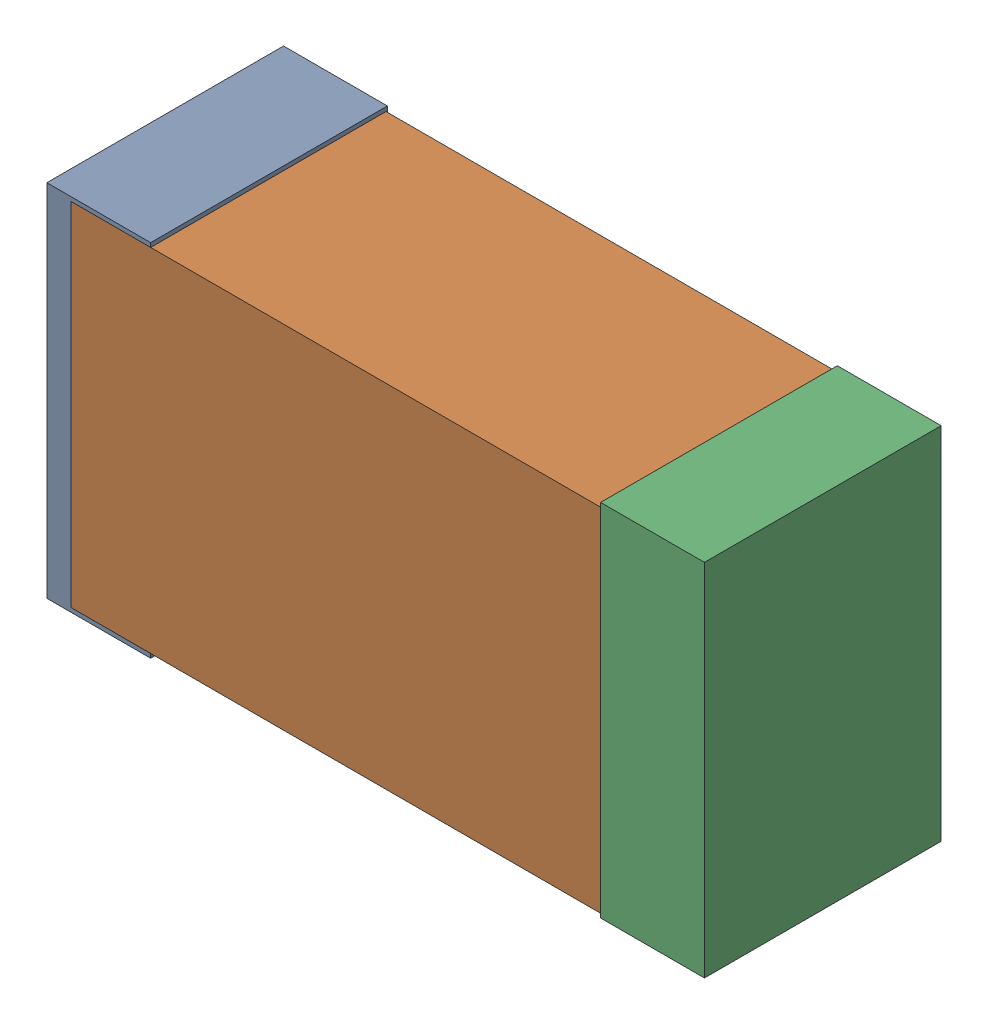
SolidWorks assembly 10kKanaloa_v2.0.0_Motor, configuration Default. Lengths in mm.
Overall size (2.38 1.3 0.85).
6 component instances, 2 part files, 0 mates.
Components (placement in the parent):
- 352877648-1: 352877648 [Default] at (69.3154 107.0102 -1.9574) size (0.38 1.3 0.85)
  - Extruded_14-1: Extruded_14 [Default] at origin size (0.38 1.3 0.85)
- 352877904-1: 352877904 [Default] at (70.3154 107.0102 -1.9524) size (2.2 1.27 0.85)
  - Extruded_18-1: Extruded_18 [Default] at origin size (2.2 1.27 0.85)
- 352877648-2: 352877648 [Default] at (71.3154 107.0102 -1.9574) size (0.38 1.3 0.85)
  - Extruded_14-1: Extruded_14 [Default] at origin size (0.38 1.3 0.85)
